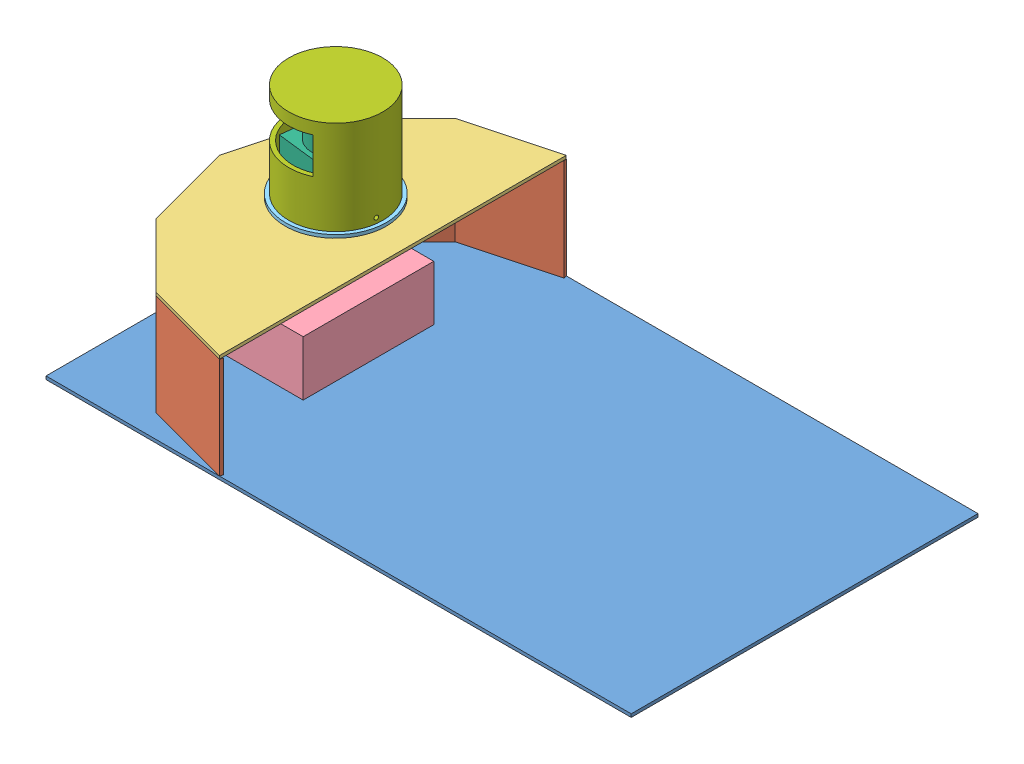
SolidWorks assembly outershell, configuration Default. Lengths in mm.
Overall size (573.53 179.83 363.98).
13 component instances, 7 part files, 27 mates.
Components (placement in the parent):
- Base-1: Base [Default] at origin size (514.35 2.79 304.8)
- hex_IR-1: hex_IR [Default] at (76.2 2.794 -20.4177) x (0.965926 0 0.258819) z (-0.258819 0 0.965926) size (78.99 88.9 2.79)
- hex_IR-2: hex_IR [Default] at (20.3428 2.794 -76.2749) x (0.707107 0 0.707107) z (-0.707107 0 0.707107) size (78.99 88.9 2.79)
- hex_IR-3: hex_IR [Default] at (0 2.794 -152.4) x (0.258819 0 0.965926) z (-0.965926 0 0.258819) size (78.99 88.9 2.79)
- hex_IR-4: hex_IR [Default] at (2.6988 2.794 -151.6769) x (0.258819 0 -0.965926) z (0.965926 0 0.258819) size (78.99 88.9 2.79)
- hex_IR-5: hex_IR [Default] at (22.3185 2.794 -226.5494) x (0.707107 0 -0.707107) z (0.707107 0 0.707107) size (78.99 88.9 2.79)
- hex_IR-6: hex_IR [Default] at (76.9231 2.794 -281.6835) x (0.965926 0 -0.258819) z (0.258819 0 0.965926) size (78.99 88.9 2.79)
- hex_hood-1: hex_hood [Default] at (152.4 91.694 -152.4) x (0.81472 0 0.579855) z (-0.579855 0 0.81472) size (240.08 2.79 275.88)
- NUC-1: NUC [Default] at (20.4177 2.794 -209.407) size (111 48.26 114.81)
- LIDAR_case-1: LIDAR_case [Default] at (43.8725 94.488 -221.1661) x (-0.116272 0 0.993217) z (-0.993217 0 -0.116272) size (88.9 93.99 88.9)
  - LIDAR_base-1: LIDAR_base [Default] at origin size (88.9 11.68 88.9)
  - LIDAR-1: LIDAR [Default] at (19.45 3.0942 -69.45) size (50 70.6 50)
  - LIDAR_top-1: LIDAR_top [Default] at (44.45 2.794 -44.45) x (0 0 -1) z (1 0 0) size (82.55 93.99 85.72)
Mates (geometry in assembly coordinates):
- Coincident1: coincident aligned: plane of Base-1 through (0 0 0) normal (0 0 1)
- Coincident2: coincident aligned: plane of Base-1 through (0 0 0) normal (0 1 0)
- Coincident3: coincident aligned: plane of Base-1 through (0 0 0) normal (1 0 0)
- Coincident4: coincident: line of Base-1 through (76.2 2.794 -20.4177) axis (0.965926 0 0.258819); plane of hex_IR-1 through (76.2 91.694 -20.4177) normal (-0.258819 0 0.965926)
- Coincident5: coincident anti-aligned: plane of Base-1 through (0 2.794 0) normal (0 1 0); plane of hex_IR-1 through (76.2 2.794 -20.4177) normal (0 -1 0)
- Coincident6: coincident: point of assembly; point of Base-1; point of hex_IR-1
- Coincident7: coincident: line of Base-1 through (20.4177 2.794 -76.2) axis (0.707107 0 0.707107); plane of hex_IR-2 through (20.3428 91.694 -76.2749) normal (-0.707107 0 0.707107)
- Coincident8: coincident anti-aligned: plane of Base-1 through (0 2.794 0) normal (0 1 0); plane of hex_IR-2 through (20.3428 2.794 -76.2749) normal (0 -1 0)
- Coincident9: coincident: point of hex_IR-1; point of hex_IR-2
- Coincident10: coincident: line of Base-1 through (0 2.794 -152.4) axis (0.258819 0 0.965926); plane of hex_IR-3 through (0 91.694 -152.4) normal (-0.965926 0 0.258819)
- Coincident11: coincident anti-aligned: plane of Base-1 through (0 2.794 0) normal (0 1 0); plane of hex_IR-3 through (0 2.794 -152.4) normal (0 -1 0)
- Coincident12: coincident: point of assembly; point of Base-1; point of hex_IR-3
- Coincident13: coincident: line of Base-1 through (20.4177 2.794 -228.6) axis (-0.258819 0 0.965926); plane of hex_IR-4 through (0 91.694 -152.4) normal (-0.965926 0 -0.258819)
- Coincident14: coincident anti-aligned: plane of Base-1 through (0 2.794 0) normal (0 1 0); plane of hex_IR-4 through (2.6988 2.794 -151.6769) normal (0 -1 0)
- Coincident15: coincident: point of hex_IR-3; point of hex_IR-4
- Coincident16: coincident: line of Base-1 through (76.2 2.794 -284.3823) axis (-0.707107 0 0.707107); plane of hex_IR-5 through (20.3428 91.694 -228.5251) normal (-0.707107 0 -0.707107)
- Coincident17: coincident anti-aligned: plane of Base-1 through (0 2.794 0) normal (0 1 0); plane of hex_IR-5 through (22.3185 2.794 -226.5494) normal (0 -1 0)
- Coincident19: coincident: point of assembly; point of Base-1; point of hex_IR-5
- Coincident20: coincident: line of Base-1 through (152.4 2.794 -304.8) axis (-0.965926 0 0.258819); plane of hex_IR-6 through (76.2 91.694 -284.3823) normal (-0.258819 0 -0.965926)
- Coincident21: coincident anti-aligned: plane of Base-1 through (0 2.794 0) normal (0 1 0); plane of hex_IR-6 through (76.9231 2.794 -281.6835) normal (0 -1 0)
- Coincident22: coincident: point of hex_IR-5; point of hex_IR-6
- Coincident23: coincident anti-aligned: plane of hex_IR-3 through (0 91.694 -152.4) normal (0 1 0); plane of hex_hood-1 through (152.4 91.694 -152.4) normal (0 -1 0)
- Coincident24: coincident aligned: plane of hex_IR-1 through (76.2 91.694 -20.4177) normal (-0.258819 0 0.965926); plane of hex_hood-1 through (76.2 94.488 -20.4177) normal (-0.258819 0 0.965926)
- Coincident25: coincident aligned: plane of hex_IR-4 through (0 91.694 -152.4) normal (-0.965926 0 -0.258819); plane of hex_hood-1 through (20.4177 94.488 -228.6) normal (-0.965926 0 -0.258819)
- Coincident26: coincident anti-aligned: plane of Base-1 through (0 2.794 0) normal (0 1 0); plane of NUC-1 through (20.4177 2.794 -94.599) normal (0 -1 0)
- Coincident27: coincident: line of Base-1 through (20.4177 2.794 -228.6) axis (0 0 1); plane of NUC-1 through (20.4177 2.794 -94.599) normal (-1 0 0)
- Coincident28: coincident anti-aligned: plane of hex_hood-1 through (152.4 94.488 -152.4) normal (0 1 0); plane of LIDAR_case-1/LIDAR_base-1 through (82.8527 94.488 -171.8493) normal (0 -1 0)
